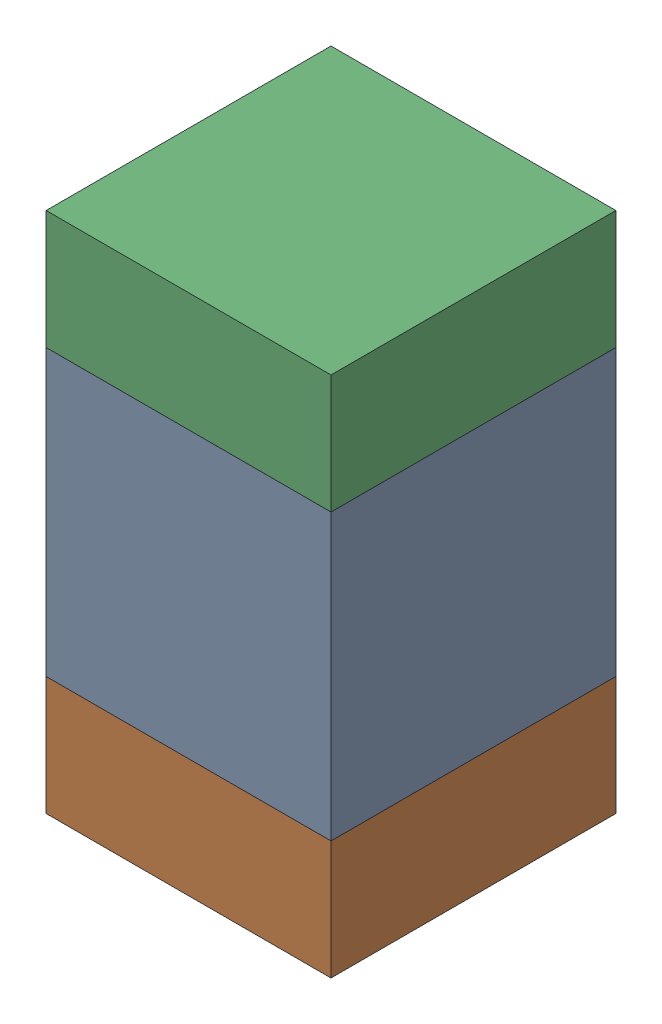
SolidWorks assembly C115_1PCB, configuration Default. Lengths in mm.
Overall size (0.6 1.1 0.6).
6 component instances, 2 part files, 0 mates.
Components (placement in the parent):
- 761606048-1: 761606048 [Default] at (114.7 110 0) size (0.6 0.6 0.6)
  - Extruded_9-1: Extruded_9 [Default] at origin size (0.6 0.6 0.6)
- 854785296-1: 854785296 [Default] at (114.7 109.575 0) size (0.6 0.25 0.6)
  - Extruded_10-1: Extruded_10 [Default] at origin size (0.6 0.25 0.6)
- 854785296-2: 854785296 [Default] at (114.7 110.425 0) size (0.6 0.25 0.6)
  - Extruded_10-1: Extruded_10 [Default] at origin size (0.6 0.25 0.6)
